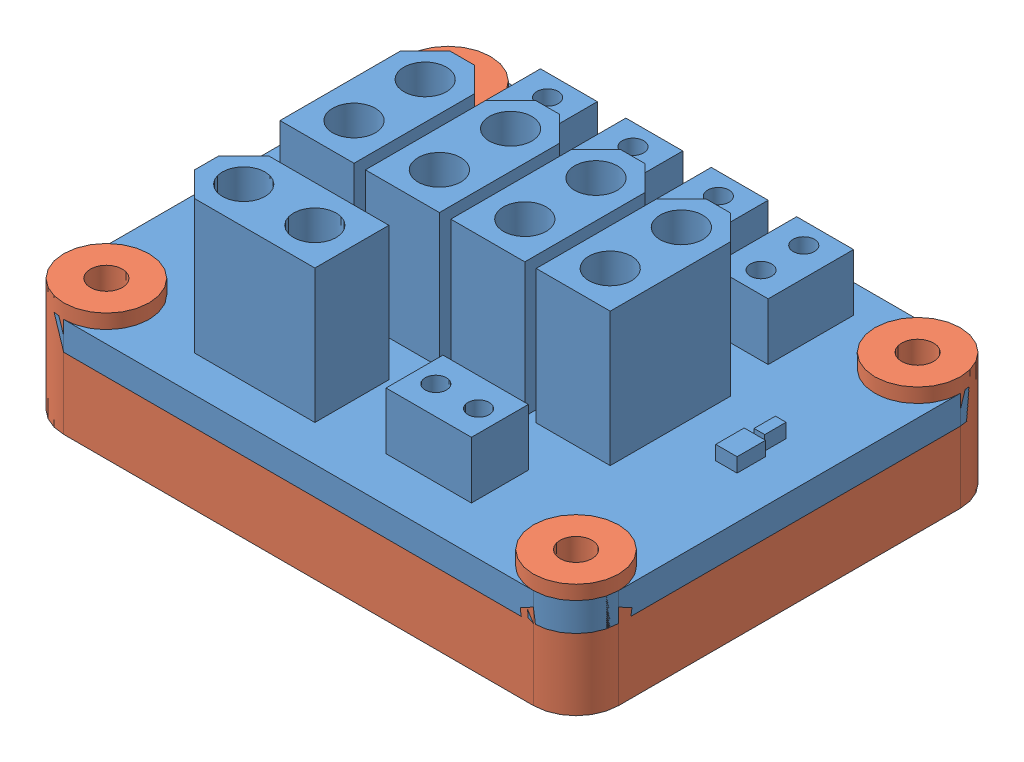
SolidWorks assembly 108 Board Holder, configuration Default. Lengths in mm.
Overall size (39 16.4 30).
2 component instances, 2 part files, 4 mates.
Components (placement in the parent):
- V4C-0108-015 Wing Drive Mainboard-1: V4C-0108-015 Wing Drive Mainboard [Default] at origin size (39 11.4 30)
- Part2^108 Board Holder-1: Part2^108 Board Holder [Default] x (-1 0 0) z (0 -1 0) size (39 30 8) (virtual)
Mates (geometry in assembly coordinates):
- InPlace1: in place: plane of V4C-0108-015 Wing Drive Mainboard-1 through (0 0 0) normal (0 -1 0); plane of Part2^108 Board Holder-1 through (0 0 0) normal (0 -1 0); moOrthogonalPlaneRef_w of V4C-0108-015 Wing Drive Mainboard-1 through (0 0 0) normal (0 -1 0); plane of Part2^108 Board Holder-1 through (0 0 0) normal (0 0 -1); plane of V4C-0108-015 Wing Drive Mainboard-1 through (0 0 0) normal (0 -1 0); plane of Part2^108 Board Holder-1 through (0 0 0) normal (-1 0 0); plane of V4C-0108-015 Wing Drive Mainboard-1 through (0 0 0) normal (0 -1 0); unknown of Part2^108 Board Holder-1
- Coincident1: coincident aligned: plane of ?; plane of ?
- Coincident2: coincident aligned: moOrthogonalPlaneRef_w of V4C-0108-015 Wing Drive Mainboard-1 through (0 0 0) normal (0 0 -1); plane of Part2^Assem1-1 through (0 0 0) normal (0 0 -1)
- Coincident3: coincident anti-aligned: moOrthogonalPlaneRef_w of V4C-0108-015 Wing Drive Mainboard-1 through (0 0 0) normal (1 0 0); plane of Part2^Assem1-1 through (0 0 0) normal (-1 0 0)
